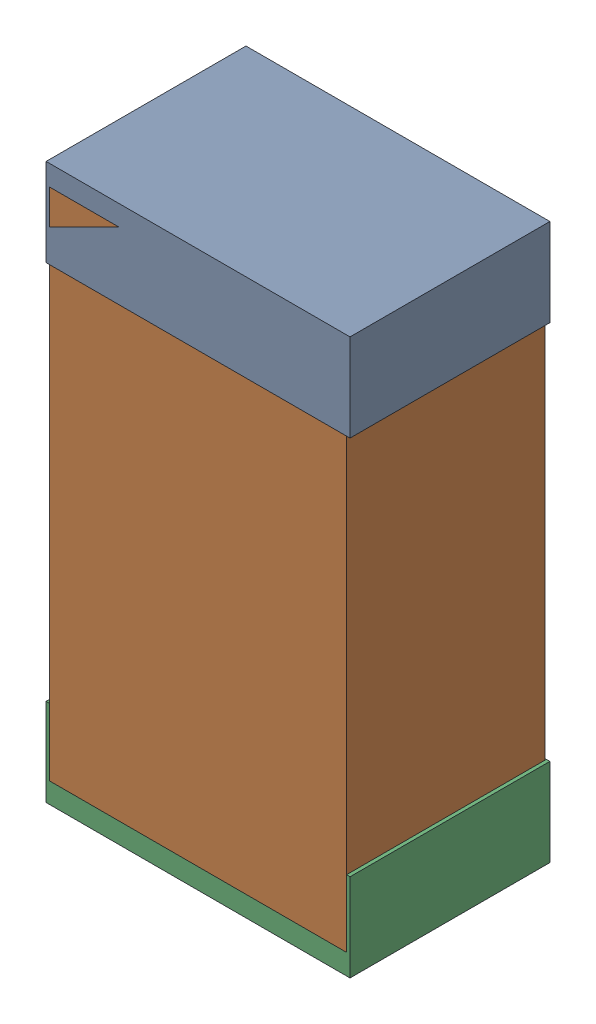
SolidWorks assembly R39Kanaloa_v2.0.0_Motor, configuration Default. Lengths in mm.
Overall size (1.3 2.38 0.85).
6 component instances, 2 part files, 0 mates.
Components (placement in the parent):
- 330415056-1: 330415056 [Default] at (94.234 128.254 -1.9574) size (1.3 0.38 0.85)
  - Extruded_2-1: Extruded_2 [Default] at origin size (1.3 0.38 0.85)
- 334787376-1: 334787376 [Default] at (94.234 127.254 -1.9524) size (1.27 2.2 0.85)
  - Extruded_16-1: Extruded_16 [Default] at origin size (1.27 2.2 0.85)
- 330415056-2: 330415056 [Default] at (94.234 126.254 -1.9574) size (1.3 0.38 0.85)
  - Extruded_2-1: Extruded_2 [Default] at origin size (1.3 0.38 0.85)
